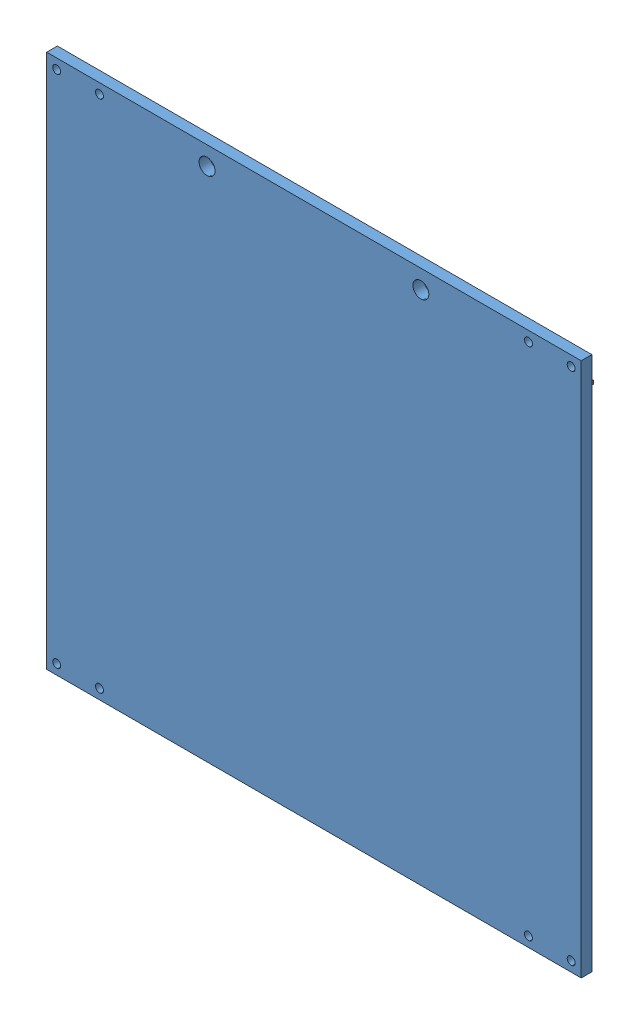
SolidWorks assembly TargetAssembly, configuration Default. Lengths in mm.
Overall size (200 200 7).
13 component instances, 2 part files, 15 mates.
Components (placement in the parent):
- Target-1: Target [Default] at (-0.712 5.2507 -5.1915) size (200 200 4)
- MPU_6050-1: MPU_6050 [Default] at (-88.962 95.7507 -6.6915) x (-1 0 0) z (0 0 -1) size (20.5 16 3)
  - MPU_6050.step-1: MPU_6050.step [Default] at origin size (20.5 16 3)
    - pcb.step-1: pcb.step [Default] at origin size (20.5 16 3)
- MPU_6050-3: MPU_6050 [Default] at (87.538 95.7507 -6.6915) x (-1 0 0) z (0 0 -1) size (20.5 16 3)
  - MPU_6050.step-1: MPU_6050.step [Default] at origin size (20.5 16 3)
    - pcb.step-1: pcb.step [Default] at origin size (20.5 16 3)
- MPU_6050-4: MPU_6050 [Default] at (87.538 -85.2493 -6.6915) x (1 0 0) z (0 0 -1) size (20.5 16 3)
  - MPU_6050.step-1: MPU_6050.step [Default] at origin size (20.5 16 3)
    - pcb.step-1: pcb.step [Default] at origin size (20.5 16 3)
- MPU_6050-5: MPU_6050 [Default] at (-88.962 -85.2493 -6.6915) x (1 0 0) z (0 0 -1) size (20.5 16 3)
  - MPU_6050.step-1: MPU_6050.step [Default] at origin size (20.5 16 3)
    - pcb.step-1: pcb.step [Default] at origin size (20.5 16 3)
Mates (geometry in assembly coordinates):
- Coincident5: coincident anti-aligned: plane of Target-1 through (-0.712 5.2507 -5.1915) normal (0 0 -1); plane of MPU_6050-3/MPU_6050.step-1/pcb.step-1 through (87.538 95.7507 -5.1915) normal (0 0 1)
- Parallel5: parallel aligned: plane of Target-1 through (99.288 -94.7493 -1.1915) normal (1 0 0); plane of MPU_6050-3/MPU_6050.step-1/pcb.step-1 through (97.788 87.7507 -6.6915) normal (1 0 0)
- Parallel6: parallel aligned: plane of Target-1 through (-100.712 105.2507 -1.1915) normal (0 1 0); plane of MPU_6050-3/MPU_6050.step-1/pcb.step-1 through (97.788 103.7507 -6.6915) normal (0 1 0)
- Coincident8: coincident anti-aligned: plane of Target-1 through (-0.712 5.2507 -5.1915) normal (0 0 -1); plane of MPU_6050-4/MPU_6050.step-1/pcb.step-1 through (87.538 -85.2493 -5.1915) normal (0 0 1)
- Parallel7: parallel anti-aligned: plane of Target-1 through (99.288 -94.7493 -1.1915) normal (1 0 0); plane of MPU_6050-4/MPU_6050.step-1/pcb.step-1 through (77.288 -77.2493 -6.6915) normal (-1 0 0)
- Parallel8: parallel aligned: plane of Target-1 through (-100.712 -94.7493 -1.1915) normal (0 -1 0); plane of MPU_6050-4/MPU_6050.step-1/pcb.step-1 through (77.288 -93.2493 -6.6915) normal (0 -1 0)
- Coincident10: coincident anti-aligned: plane of Target-1 through (-0.712 5.2507 -5.1915) normal (0 0 -1); plane of MPU_6050-5/MPU_6050.step-1/pcb.step-1 through (-88.962 -85.2493 -5.1915) normal (0 0 1)
- Parallel9: parallel aligned: plane of Target-1 through (-100.712 -94.7493 -1.1915) normal (0 -1 0); plane of MPU_6050-5/MPU_6050.step-1/pcb.step-1 through (-99.212 -93.2493 -6.6915) normal (0 -1 0)
- Parallel10: parallel aligned: plane of Target-1 through (-100.712 -94.7493 -1.1915) normal (-1 0 0); plane of MPU_6050-5/MPU_6050.step-1/pcb.step-1 through (-99.212 -77.2493 -6.6915) normal (-1 0 0)
- Concentric1: concentric aligned: cylinder of Target-1 through (95.538 101.5007 -1.1915) axis (0 0 1) radius 1.5; cylinder of MPU_6050-3/MPU_6050.step-1/pcb.step-1 through (95.538 101.5007 -6.6915) axis (0 0 1) radius 1.5
- Concentric3: concentric aligned: cylinder of Target-1 through (95.538 -90.9993 -1.1915) axis (0 0 1) radius 1.5; cylinder of MPU_6050-4/MPU_6050.step-1/pcb.step-1 through (95.538 -90.9993 -6.6915) axis (0 0 1) radius 1.5
- Concentric4: concentric aligned: cylinder of Target-1 through (-80.962 -90.9993 -1.1915) axis (0 0 1) radius 1.5; cylinder of MPU_6050-5/MPU_6050.step-1/pcb.step-1 through (-80.962 -90.9993 -6.6915) axis (0 0 1) radius 1.5
- Concentric5: concentric aligned: cylinder of Target-1 through (-80.962 101.5007 -1.1915) axis (0 0 1) radius 1.5; cylinder of MPU_6050-1/MPU_6050.step-1/pcb.step-1 through (-80.962 101.5007 -6.6915) axis (0 0 1) radius 1.5
- Concentric6: concentric aligned: cylinder of Target-1 through (-96.962 101.5007 -1.1915) axis (0 0 1) radius 1.5; cylinder of MPU_6050-1/MPU_6050.step-1/pcb.step-1 through (-96.962 101.5007 -6.6915) axis (0 0 1) radius 1.5
- Coincident12: coincident anti-aligned: plane of Target-1 through (-0.712 5.2507 -5.1915) normal (0 0 -1); plane of MPU_6050-1/MPU_6050.step-1/pcb.step-1 through (-88.962 95.7507 -5.1915) normal (0 0 1)
